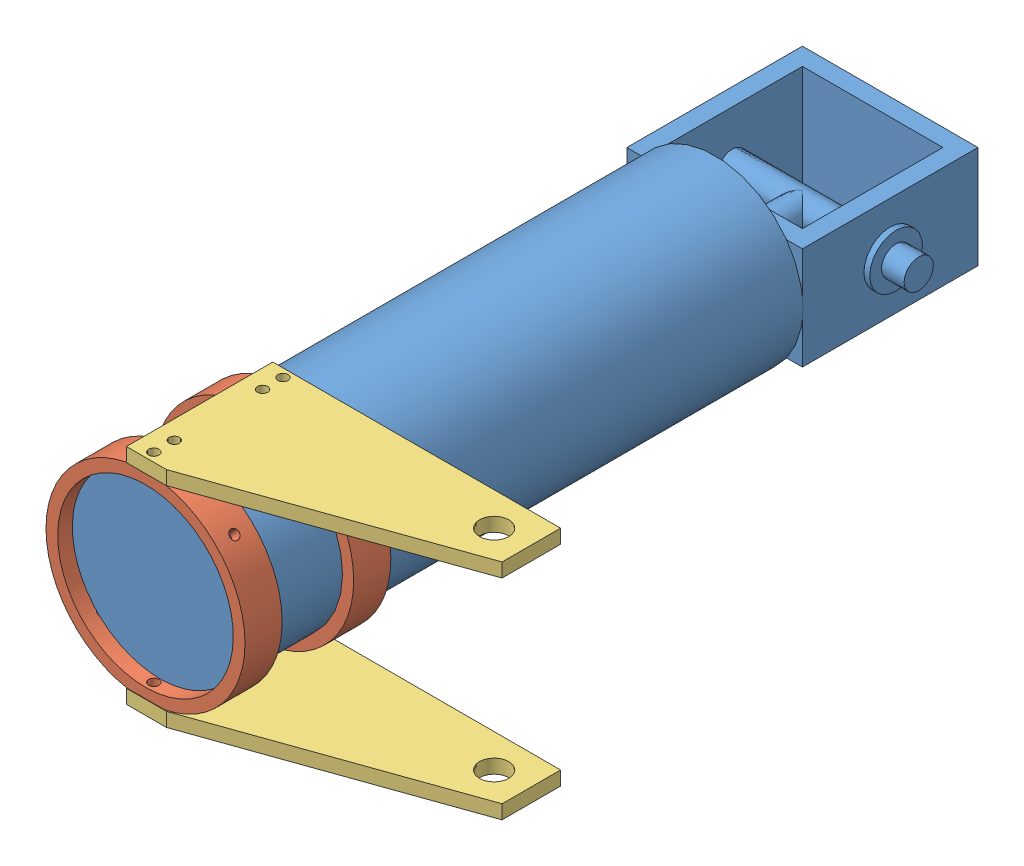
SolidWorks assembly Ensamblaje2, configuration Predeterminado. Lengths in mm.
Overall size (140.08 96.17 254.65).
5 component instances, 3 part files, 11 mates.
Components (placement in the parent):
- EslabonSimplificado-1: EslabonSimplificado [Predeterminado] at origin size (79.5 60.33 249.5)
- SujeccionMotorV2-1: SujeccionMotorV2 [Predeterminado] at (0 0 181) x (0.707107 -0.707107 0) z (0 0 1) size (68 68 12.7)
- Soporte-1: Soporte [Predeterminado] at (-6.35 -38.1643 174.65) x (0 0 -1) z (0 1 0) size (50 98.35 4.76)
- SujeccionMotorV2-2: SujeccionMotorV2 [Predeterminado] at (0 0 218.15) x (0.707107 -0.707107 0) z (0 0 1) size (68 68 12.7)
- Soporte-2: Soporte [Predeterminado] at (-6.35 33.4018 174.65) x (0 0 -1) z (0 1 0) size (50 98.35 4.76)
Mates (geometry in assembly coordinates):
- Concéntrica2: concentric aligned: cylinder of EslabonSimplificado-1 through (0 0 30) axis (0 0 1) radius 30.165; cylinder of SujeccionMotorV2-2 through (0 0 211.8) axis (0 0 1) radius 30
- Concéntrica3: concentric aligned: cylinder of EslabonSimplificado-1 through (0 0 30) axis (0 0 1) radius 30.165; cylinder of SujeccionMotorV2-1 through (0 0 174.65) axis (0 0 1) radius 30
- Paralelo2: parallel aligned: plane of EslabonSimplificado-1 through (0 -17.5 0) normal (0 -1 0); plane of SujeccionMotorV2-1 through (6.35 -33.4018 174.65) normal (0 -1 0)
- Paralelo3: parallel aligned: plane of SujeccionMotorV2-1 through (6.35 -33.4018 174.65) normal (0 -1 0); plane of SujeccionMotorV2-2 through (6.35 -33.4018 211.8) normal (0 -1 0)
- Distancia1: distance = 5 mm aligned: plane of EslabonSimplificado-1 through (0 0 219.5) normal (0 0 1); plane of SujeccionMotorV2-2 through (0 0 224.5) normal (0 0 1)
- Concéntrica4: concentric: cylinder of Soporte-1 through (0 -33.4018 221.65) axis (0 -1 0) radius 1.75; cylinder of SujeccionMotorV2-2 through (0 -48.0833 221.65) axis (0 1 0) radius 1.75
- Concéntrica5: concentric: cylinder of SujeccionMotorV2-1 through (0 -48.0833 184.5) axis (0 1 0) radius 1.75; cylinder of Soporte-1 through (0 -33.4018 184.5) axis (0 -1 0) radius 1.75
- Coincidente1: coincident anti-aligned: plane of Soporte-1 through (-6.35 -33.4018 174.65) normal (0 1 0); plane of SujeccionMotorV2-2 through (6.35 -33.4018 211.8) normal (0 -1 0)
- Coincidente2: coincident: plane of SujeccionMotorV2-2 through (6.35 33.4018 211.8) normal (0 1 0); plane of Soporte-2 through (-6.35 33.4018 174.65) normal (0 -1 0)
- Concéntrica6: concentric: cylinder of SujeccionMotorV2-2 through (0 -48.0833 221.65) axis (0 1 0) radius 1.75; cylinder of Soporte-2 through (0 38.1643 221.65) axis (0 -1 0) radius 1.75
- Concéntrica7: concentric anti-aligned: cylinder of SujeccionMotorV2-1 through (0 -48.0833 184.5) axis (0 1 0) radius 1.75; cylinder of Soporte-2 through (0 38.1643 184.5) axis (0 -1 0) radius 1.75
